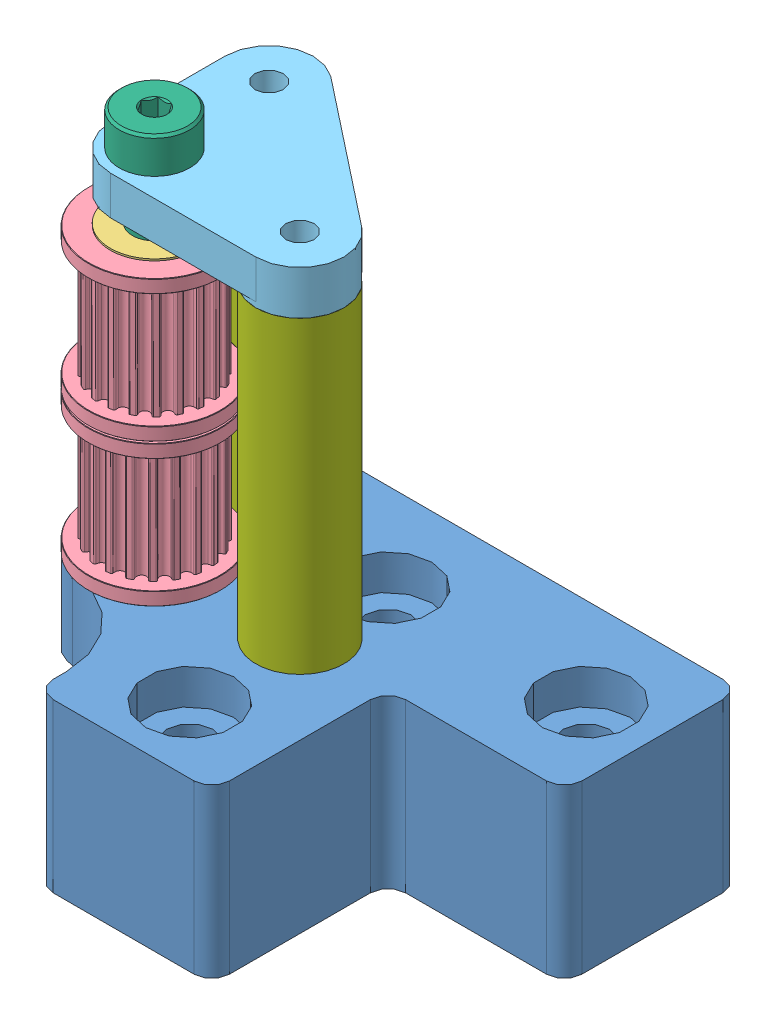
SolidWorks assembly 4040_double_pulley_corner_bracket_left, configuration Default. Lengths in mm.
Overall size (56.94 63.81 40).
10 component instances, 7 part files, 21 mates.
Components (placement in the parent):
- 4040_double_pulley_corner_bracket-1: 4040_double_pulley_corner_bracket [Left Corner Pulley Plate] at origin size (53 19.81 40)
- m4_heat_set_insert_long_94180A353-1: m4_heat_set_insert_long_94180A353 [94180A353] at (-6.5 19 -20) size (6.35 8.38 6.35)
- m5_shim_0.2mm_thick_98089A246-1: m5_shim_0.2mm_thick_98089A246 [98089A246] at (-6.5 19.2 -20) x (0.982477 0 0.186382) z (0.186382 0 -0.982477) size (10 0.2 10)
- Gates_20T_12mm_toothed_idler_5mm_bore-1: Gates_20T_12mm_toothed_idler_5mm_bore [Default] at (-6.5 27.7758 -20) x (0.821855 0 -0.569697) z (0.569697 0 0.821855) size (15 16 15)
- m5_shim_0.2mm_thick_98089A246-2: m5_shim_0.2mm_thick_98089A246 [98089A246] at (-6.5 35.4 -20) x (0.837169 0 0.546944) z (0.546944 0 -0.837169) size (10 0.2 10)
- Gates_20T_12mm_toothed_idler_5mm_bore-2: Gates_20T_12mm_toothed_idler_5mm_bore [Default] at (-6.5 43.9758 -20) x (0.332407 0 0.943136) z (-0.943136 0 0.332407) size (15 16 15)
- m5_shim_0.2mm_thick_98089A246-4: m5_shim_0.2mm_thick_98089A246 [98089A246] at (-6.5 51.6 -20) x (0.837169 0 0.546944) z (0.546944 0 -0.837169) size (10 0.2 10)
- back_pulley_reinforcement_plate-1: back_pulley_reinforcement_plate [Left Corner Pulley Reinforcement Plate] at (-6.5 54.6 -20) size (26.5 5 23)
- m4_shoulder_screw_5mm_d_40mm_l-1: m4_shoulder_screw_5mm_d_40mm_l [90278A375] at (-6.5 63 -20) x (-0.836792 0 0.54752) z (0 1 0) size (8 8 49.24)
- double_pulley_reinforcement_plate_support-1: double_pulley_reinforcement_plate_support [Default] at (10 54 -33) x (1 0 0) z (0 -1 0) size (26.5 23 35)
Mates (geometry in assembly coordinates):
- Coincident1: coincident aligned: plane of 4040_double_pulley_corner_bracket-1 through (0 19 0) normal (0 1 0); plane of m4_heat_set_insert_long_94180A353-1 through (-6.5 19 -20) normal (0 1 0)
- Concentric1: concentric aligned: circle of 4040_double_pulley_corner_bracket-1; circle of m4_heat_set_insert_long_94180A353-1
- Concentric21: concentric anti-aligned: cylinder of 4040_double_pulley_corner_bracket-1 through (-6.5 19 -20) axis (0 -1 0) radius 2.7; cylinder of m5_shim_0.2mm_thick_98089A246-1 through (-6.5 19 -20) axis (0 1 0) radius 5
- Concentric31: concentric aligned: cone of Gates_20T_12mm_toothed_idler_5mm_bore-1 through (-6.5 35.15 -20) axis (0 1 0); cylinder of m5_shim_0.2mm_thick_98089A246-2 through (-6.5 35.2 -20) axis (0 1 0) radius 5
- Coincident31: coincident anti-aligned: plane of Gates_20T_12mm_toothed_idler_5mm_bore-1 through (-6.5 35.2 -20) normal (0 1 0); plane of m5_shim_0.2mm_thick_98089A246-2 through (-6.5 35.2 -20) normal (0 -1 0)
- Concentric61: concentric anti-aligned: cone of Gates_20T_12mm_toothed_idler_5mm_bore-2 through (-6.5 51.4 -20) axis (0 -1 0); cylinder of m5_shim_0.2mm_thick_98089A246-4 through (-6.5 51.4 -20) axis (0 1 0) radius 5
- Coincident61: coincident anti-aligned: plane of Gates_20T_12mm_toothed_idler_5mm_bore-2 through (-6.5 51.4 -20) normal (0 1 0); plane of m5_shim_0.2mm_thick_98089A246-4 through (-6.5 51.4 -20) normal (0 -1 0)
- Concentric71: concentric aligned: circle of m4_heat_set_insert_long_94180A353-1; circle of m5_shim_0.2mm_thick_98089A246-1
- Concentric81: concentric anti-aligned: circle of m5_shim_0.2mm_thick_98089A246-1; circle of Gates_20T_12mm_toothed_idler_5mm_bore-1
- Coincident71: coincident anti-aligned: plane of m5_shim_0.2mm_thick_98089A246-1 through (-6.5 19.2 -20) normal (0 1 0); plane of Gates_20T_12mm_toothed_idler_5mm_bore-1 through (-6.5 19.2 -20) normal (0 -1 0)
- Concentric91: concentric aligned: circle of m5_shim_0.2mm_thick_98089A246-2; circle of Gates_20T_12mm_toothed_idler_5mm_bore-2
- Coincident81: coincident anti-aligned: plane of m5_shim_0.2mm_thick_98089A246-2 through (-6.5 35.4 -20) normal (0 1 0); plane of Gates_20T_12mm_toothed_idler_5mm_bore-2 through (-6.5 35.4 -20) normal (0 -1 0)
- Concentric121: concentric aligned: cylinder of Gates_20T_12mm_toothed_idler_5mm_bore-2 through (-6.5 31.0876 -20) axis (0 -1 0) radius 2.5; cylinder of m4_shoulder_screw_5mm_d_40mm_l-1 through (-6.5 14 -20) axis (0 -1 0) radius 2.5
- Coincident111: coincident anti-aligned: plane of m4_heat_set_insert_long_94180A353-1 through (-6.5 19 -20) normal (0 1 0); plane of m4_shoulder_screw_5mm_d_40mm_l-1 through (-7.8688 19 -22.092) normal (0 -1 0)
- Coincident121: coincident anti-aligned: plane of 4040_double_pulley_corner_bracket-1 through (0 19 0) normal (0 1 0); plane of m5_shim_0.2mm_thick_98089A246-1 through (-6.5 19 -20) normal (0 -1 0)
- Concentric131: concentric aligned: cylinder of back_pulley_reinforcement_plate-1 through (-6.5 56.17 -20) axis (0 -1 0) radius 2.5; cylinder of m4_shoulder_screw_5mm_d_40mm_l-1 through (-6.5 14 -20) axis (0 -1 0) radius 2.5
- Concentric161: concentric aligned: cylinder of 4040_double_pulley_corner_bracket-1 through (10 19 -20) axis (0 -1 0) radius 1.6; cylinder of back_pulley_reinforcement_plate-1 through (10 56.17 -20) axis (0 -1 0) radius 1.6
- Concentric171: concentric aligned: cylinder of 4040_double_pulley_corner_bracket-1 through (-6.5 19 -33) axis (0 -1 0) radius 1.6; cylinder of back_pulley_reinforcement_plate-1 through (-6.5 56.17 -33) axis (0 -1 0) radius 1.6
- Coincident151: coincident anti-aligned: plane of back_pulley_reinforcement_plate-1 through (10 59 -20) normal (0 1 0); plane of m4_shoulder_screw_5mm_d_40mm_l-1 through (-8.6901 59 -23.3472) normal (0 -1 0)
- Coincident16: coincident anti-aligned: plane of back_pulley_reinforcement_plate-1 through (-6.5 54 -33) normal (0 -1 0); plane of double_pulley_reinforcement_plate_support-1 through (10 54 -33) normal (0 1 0)
- Concentric18: concentric anti-aligned: cylinder of back_pulley_reinforcement_plate-1 through (-6.5 56.17 -33) axis (0 -1 0) radius 1.6; cylinder of double_pulley_reinforcement_plate_support-1 through (-6.5 19 -33) axis (0 1 0) radius 1.6
